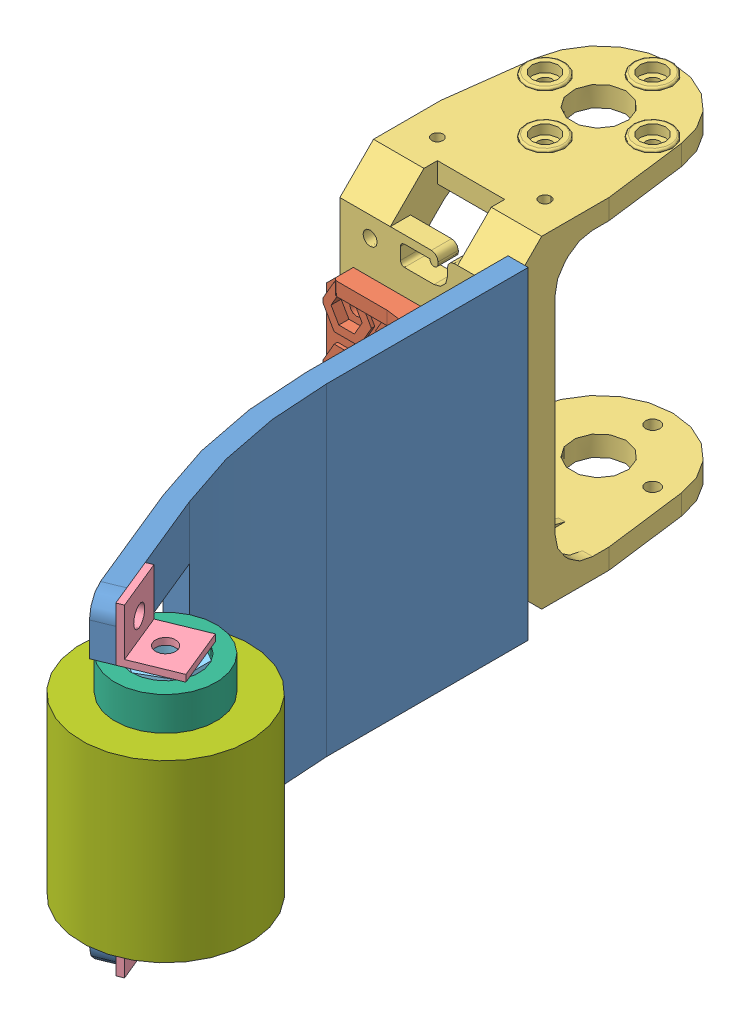
SolidWorks assembly essai_assemblage_pince_2, configuration Default. Lengths in mm.
Overall size (55.93 48.81 118.84).
8 component instances, 7 part files, 18 mates.
Components (placement in the parent):
- essai_pince_5-1: essai_pince_5 [Default] at (-8.4781 -11.6289 -22.4125) size (15.55 48 75)
- F9ORG-1: F9ORG [Défaut] at (-8.4781 12.3711 -52.4125) x (1 0 0) z (0 0 -1) size (24 24 30)
- F2-1: F2 [Défaut] at (-20.9781 12.3711 -78.4125) x (0 1 0) z (0 0 1) size (48.81 25 37)
- corniere_8x8-1: corniere_8x8 [Default] at (11.4493 28.3711 11.02) x (-0.925648 0 0.378386) z (-0.378386 0 -0.925648) size (8 8 8)
- corniere_8x8-2: corniere_8x8 [Default] at (14.4764 -3.6289 18.4252) x (-0.925648 0 0.378386) z (0.378386 0 0.925648) size (8 8 8)
- entretoise_M5_L32-1: entretoise_M5_L32 [Default] at (9.2602 -3.6289 16.2362) size (8.66 32 10)
- Support_Rouleau_D15_H20-1: Support_Rouleau_D15_H20 [Default] at (9.2602 23.3711 16.2362) x (0.999025 0 0.044138) z (-0.044138 0 0.999025) size (15 20 15)
- Rouleau_D25_H26-1: Rouleau_D25_H26 [Default] at (9.2602 -2.6289 16.2362) x (0.998395 0 -0.056627) z (0.056627 0 0.998395) size (25 26 25)
Mates (geometry in assembly coordinates):
- Coïncidente1: coincident anti-aligned: plane of essai_pince_5-1 through (-8.4781 36.3711 -22.4125) normal (-1 0 0); plane of F9ORG-1 through (-8.4781 24.3711 -52.4125) normal (1 0 0)
- Coïncidente2: coincident aligned: plane of essai_pince_5-1 through (-8.4781 36.3711 -52.4125) normal (0 0 -1); plane of F9ORG-1 through (-33.4781 24.3711 -52.4125) normal (0 0 -1)
- Coïncidente3: coincident anti-aligned: plane of F9ORG-1 through (-33.4781 24.3711 -52.4125) normal (0 0 -1); plane of F2-1 through (-33.4781 -11.6289 -52.4125) normal (0 0 1)
- Coïncidente4: coincident aligned: plane of F9ORG-1 through (-8.4781 24.3711 -52.4125) normal (1 0 0); plane of F2-1 through (-8.4781 -11.6289 -52.4125) normal (1 0 0)
- Coaxiale3: concentric anti-aligned: cylinder of F9ORG-1; cylinder of F2-1
- Coïncidente5: coincident anti-aligned: plane of corniere_8x8-1 through (4.0441 29.3711 14.0471) normal (-0.925648 0 0.378386); plane of essai_pince_5-1 through (-0.4965 36.3711 2.9393) normal (0.925648 0 -0.378386)
- Coaxiale4: concentric aligned: cylinder of essai_pince_5-1; cylinder of corniere_8x8-1
- Coïncidente6: coincident aligned: plane of essai_pince_5-1 through (4.2942 36.3711 22.5875) normal (0.378386 0 0.925648); plane of corniere_8x8-1 through (14.4764 29.3711 18.4252) normal (0.378386 0 0.925648)
- Coaxiale5: concentric aligned: cylinder of essai_pince_5-1; cylinder of corniere_8x8-2
- Coïncidente7: coincident anti-aligned: plane of essai_pince_5-1 through (-0.4965 36.3711 2.9393) normal (0.925648 0 -0.378386); plane of corniere_8x8-2 through (7.0712 -4.6289 21.4523) normal (-0.925648 0 0.378386)
- Coïncidente8: coincident aligned: plane of essai_pince_5-1 through (4.2942 36.3711 22.5875) normal (0.378386 0 0.925648); plane of corniere_8x8-2 through (14.4764 -4.6289 18.4252) normal (0.378386 0 0.925648)
- Coaxiale6: concentric aligned: cylinder of corniere_8x8-1; cylinder of entretoise_M5_L32-1
- Coïncidente9: coincident anti-aligned: plane of corniere_8x8-1 through (14.4764 28.3711 18.4252) normal (0 -1 0); plane of entretoise_M5_L32-1 through (9.2602 28.3711 11.2362) normal (0 1 0)
- Coaxiale7: concentric anti-aligned: cylinder of entretoise_M5_L32-1; cylinder of Support_Rouleau_D15_H20-1
- Coïncidente10: coincident anti-aligned: plane of essai_pince_5-1 through (32.9437 28.3711 10.8761) normal (0 -1 0); plane of Support_Rouleau_D15_H20-1 through (9.2602 28.3711 16.2362) normal (0 1 0)
- Coïncidente12: coincident aligned: plane of essai_pince_5-1 through (61.5219 36.3711 -22.4125) normal (0 1 0); plane of F2-1 through (-20.9781 36.3711 -78.4125) normal (0 1 0)
- Coaxiale8: concentric: cylinder of Support_Rouleau_D15_H20-1; cylinder of ?
- Coïncidente14: coincident anti-aligned: plane of Support_Rouleau_D15_H20-1 through (9.2602 23.3711 16.2362) normal (0 -1 0); plane of ? through (9.2602 20.6185 16.2362) normal (0 1 0)
